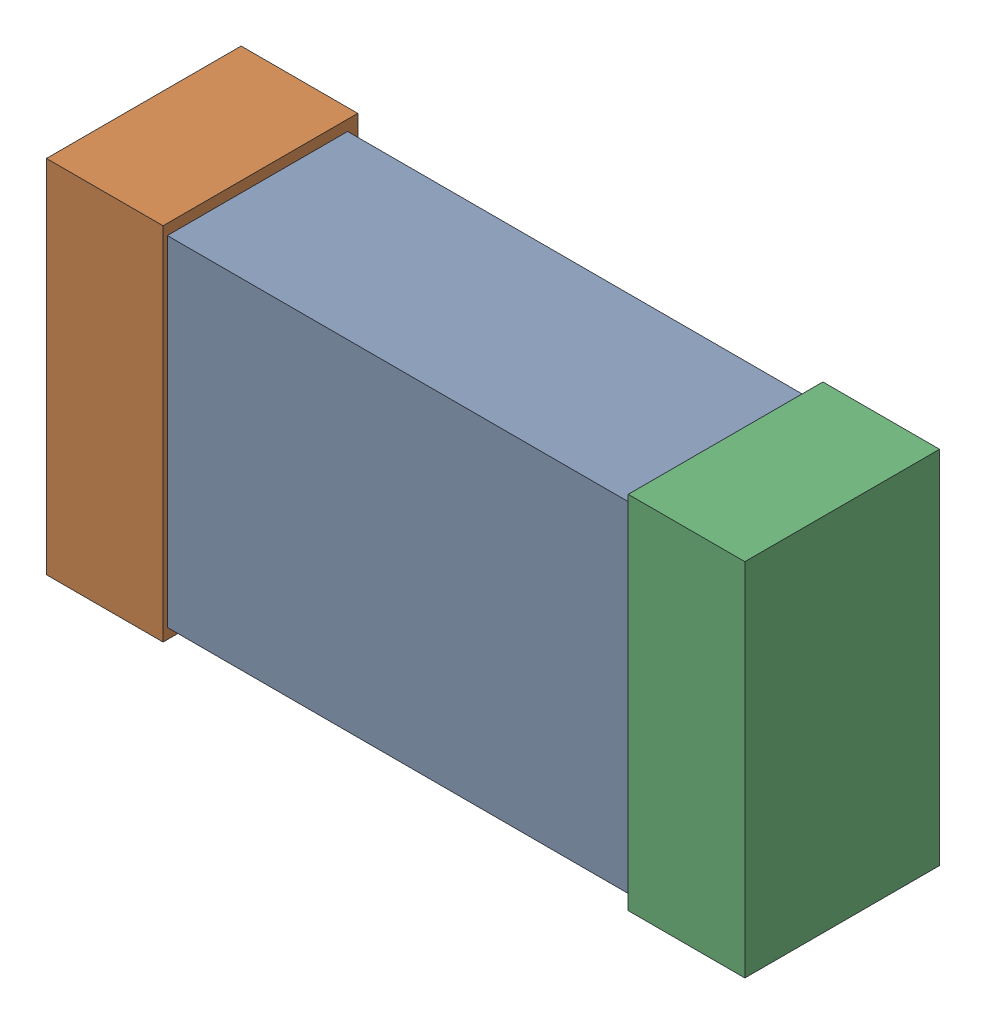
SolidWorks assembly R4, configuration Default. Lengths in mm.
Overall size (1.65 0.85 0.46).
6 component instances, 2 part files, 0 mates.
Components (placement in the parent):
- 432120720_15-1: 432120720_15 [Default] at (28.5459 18.3613 0.025) size (1.5 0.8 0.42)
  - Extruded (12)-1: Extruded (12) [Default] at origin size (1.5 0.8 0.42)
- 432120464_32-1: 432120464_32 [Default] at (27.8601 18.3613 0.001) size (0.28 0.85 0.46)
  - Extruded (11)-1: Extruded (11) [Default] at origin size (0.28 0.85 0.46)
- 432120464_33-1: 432120464_33 [Default] at (29.2316 18.3613 0.001) size (0.28 0.85 0.46)
  - Extruded (11)-1: Extruded (11) [Default] at origin size (0.28 0.85 0.46)
